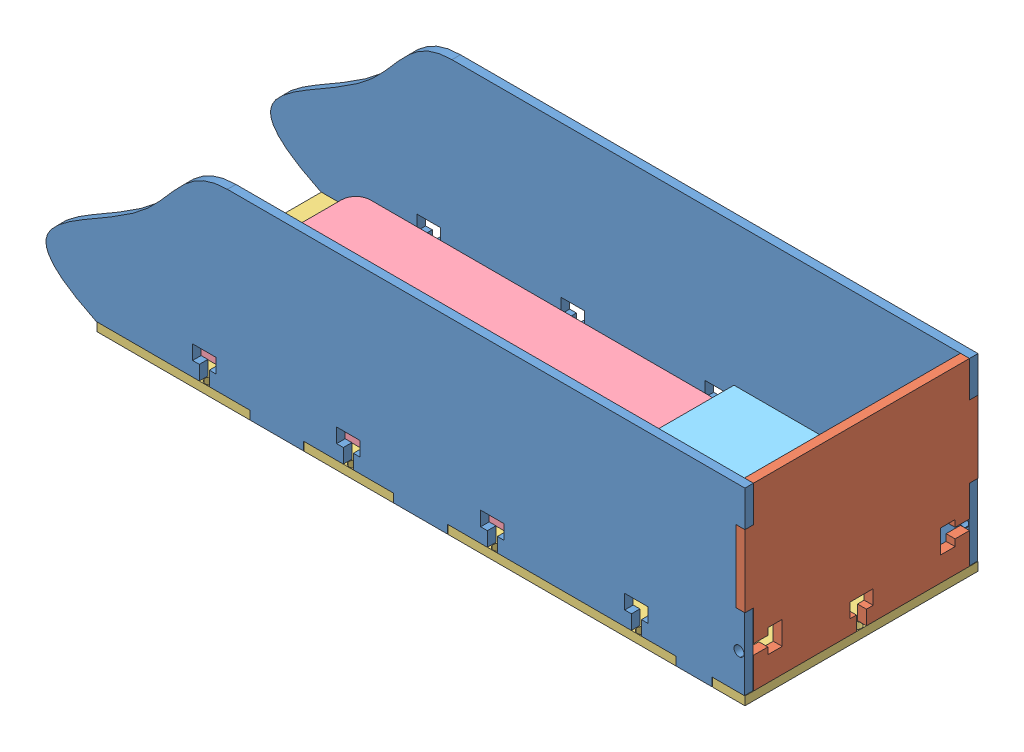
SolidWorks assembly plane, configuration Default. Lengths in mm.
Overall size (249.43 66.5 82.2).
6 component instances, 5 part files, 16 mates.
Components (placement in the parent):
- plane_side-1: plane_side [Default] at (68.347 137.5135 199.2949) size (249.43 66.5 3)
- plane_back-2: plane_back [Default] at (179.647 137.5135 161.1949) size (3.17 63.5 82.2)
- plane_side-2: plane_side [Default] at (68.347 137.5135 120.0949) size (249.43 66.5 3)
- plane_btm-1: plane_btm [Default] at (68.522 102.7635 161.1949) size (228.6 3 82.2)
- phone-1: phone [Default] at (36.7044 105.7635 161.4019) x (0 0 -1) z (0 1 0) size (65.79 129.79 11.68)
- pcb-1: pcb [Default] at (140.9608 135.7635 164.2949) x (1 0 0) z (0 -1 0) size (50 50 30)
Mates (geometry in assembly coordinates):
- Coincident5: coincident aligned: plane of plane_side-1 through (179.472 105.7635 202.2949) normal (0 -1 0); plane of plane_back-2 through (182.822 105.7635 199.2949) normal (0 -1 0)
- Coincident6: coincident anti-aligned: plane of plane_side-1 through (179.647 156.5635 202.2949) normal (1 0 0); plane of plane_back-2 through (179.647 137.5135 161.1949) normal (-1 0 0)
- Coincident7: coincident aligned: plane of plane_side-1 through (182.822 169.2635 202.2949) normal (1 0 0); plane of plane_back-2 through (182.822 137.5135 161.1949) normal (1 0 0)
- Coincident8: coincident aligned: plane of plane_side-1 through (-43.7675 138.5364 202.2949) normal (0 0 1); plane of plane_back-2 through (182.822 156.5635 202.2949) normal (0 0 1)
- Coincident9: coincident aligned: plane of plane_back-2 through (182.822 137.5135 161.1949) normal (1 0 0); plane of plane_side-2 through (182.822 169.2635 123.0949) normal (1 0 0)
- Coincident10: coincident aligned: plane of plane_back-2 through (182.822 105.7635 146.7296) normal (0 -1 0); plane of plane_side-2 through (179.472 105.7635 123.0949) normal (0 -1 0)
- Coincident11: coincident aligned: plane of plane_back-2 through (182.822 156.5635 120.0949) normal (0 0 -1); plane of plane_side-2 through (-43.7675 138.5364 120.0949) normal (0 0 -1)
- Coincident17: coincident aligned: plane of plane_side-1 through (-43.7675 138.5364 202.2949) normal (0 0 1); plane of plane_btm-1 through (-6.3491 105.7635 202.2949) normal (0 0 1)
- Coincident18: coincident aligned: plane of plane_back-2 through (182.822 137.5135 161.1949) normal (1 0 0); plane of plane_btm-1 through (182.822 105.7635 120.0949) normal (1 0 0)
- Coincident19: coincident anti-aligned: plane of plane_side-1 through (179.472 105.7635 202.2949) normal (0 -1 0); plane of plane_btm-1 through (68.522 105.7635 161.1949) normal (0 1 0)
- Coincident20: coincident anti-aligned: plane of plane_btm-1 through (68.522 105.7635 161.1949) normal (0 1 0); plane of phone-1 through (36.7044 105.7635 161.4019) normal (0 -1 0)
- Parallel1: parallel aligned: plane of plane_btm-1 through (-45.778 105.7635 120.0949) normal (-1 0 0); plane of phone-1 through (-28.1926 117.4475 194.2949) normal (-1 0 0)
- Distance1: distance = 5 mm anti-aligned: plane of phone-1 through (101.6014 117.4475 194.2949) normal (0 0 1); plane of plane_side-1 through (-43.7675 138.5364 199.2949) normal (0 0 -1)
- Coincident23: coincident anti-aligned: plane of plane_btm-1 through (68.522 105.7635 161.1949) normal (0 1 0); plane of pcb-1 through (140.9608 105.7635 164.2949) normal (0 -1 0)
- Parallel2: parallel aligned: plane of plane_btm-1 through (-45.778 105.7635 120.0949) normal (-1 0 0); plane of pcb-1 through (115.9608 105.7635 139.2949) normal (-1 0 0)
- Distance2: distance = 10 mm anti-aligned: plane of pcb-1 through (115.9608 105.7635 189.2949) normal (0 0 1); plane of plane_side-1 through (-43.7675 138.5364 199.2949) normal (0 0 -1)
